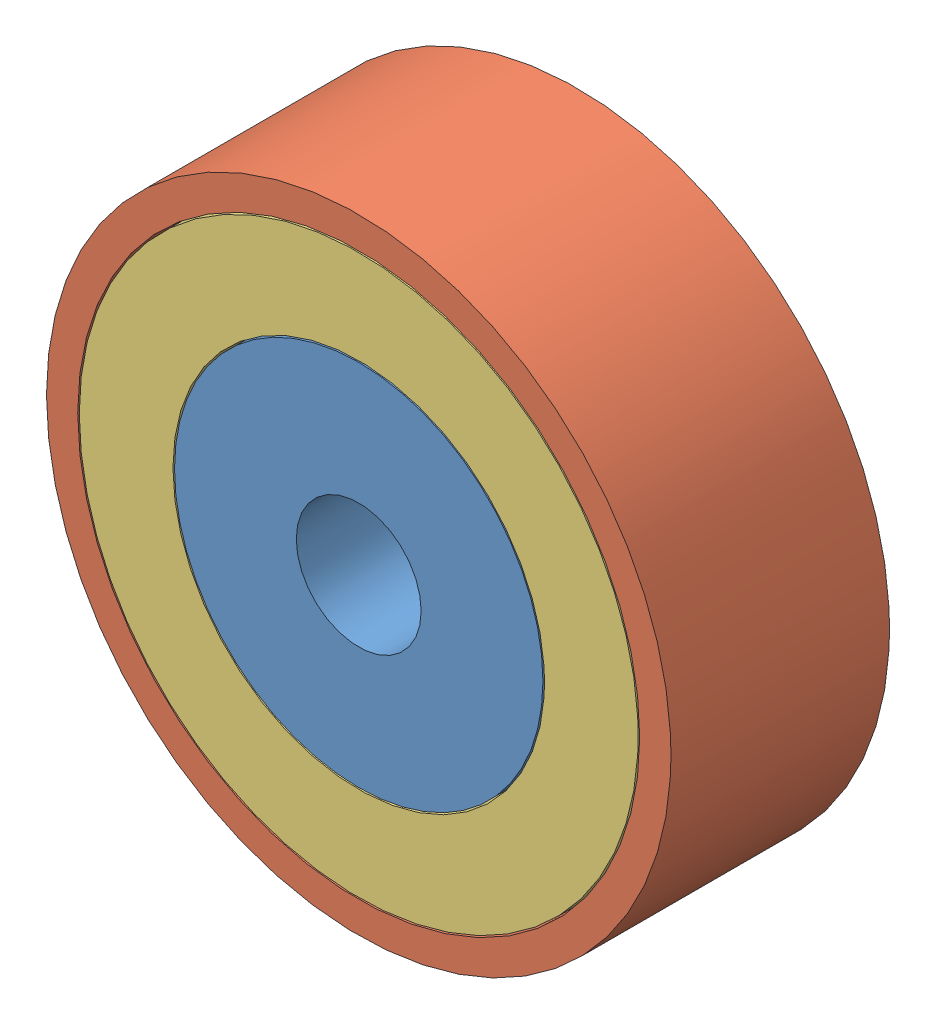
SolidWorks assembly 轴承, configuration 默认. Lengths in mm.
Overall size (20 20 7).
3 component instances, 3 part files, 4 mates.
Components (placement in the parent):
- 轴承内圈-1: 轴承内圈 [默认] at (-5.0655 0.8032 6.5) size (11.8 11.8 7)
- 轴承外圈-1: 轴承外圈 [默认] at (-5.0655 0.8032 6.5) size (20 20 7)
- 轴承中圈-1: 轴承中圈 [默认] at (-5.0655 0.8032 6.5) size (17.9 17.9 7)
Mates (geometry in assembly coordinates):
- 重合1: coincident: plane of ? through (-5.0655 0.8032 13.5) normal (0 0 1); plane of ? through (-5.0655 0.8032 13.5) normal (0 0 1)
- 重合2: coincident: plane of ? through (-5.0655 0.8032 13.5) normal (0 0 1); plane of ? through (-5.0655 0.8032 13.5) normal (0 0 1)
- 同心1: concentric: cylinder of ? through (-5.0655 0.8032 13.5) axis (0 0 -1) radius 9; cylinder of ? through (-5.0655 0.8032 13.5) axis (0 0 -1) radius 8.95
- 同心2: concentric: cylinder of ? through (-5.0655 0.8032 13.5) axis (0 0 -1) radius 5.9; cylinder of ? through (-5.0655 0.8032 13.5) axis (0 0 -1) radius 5.95
